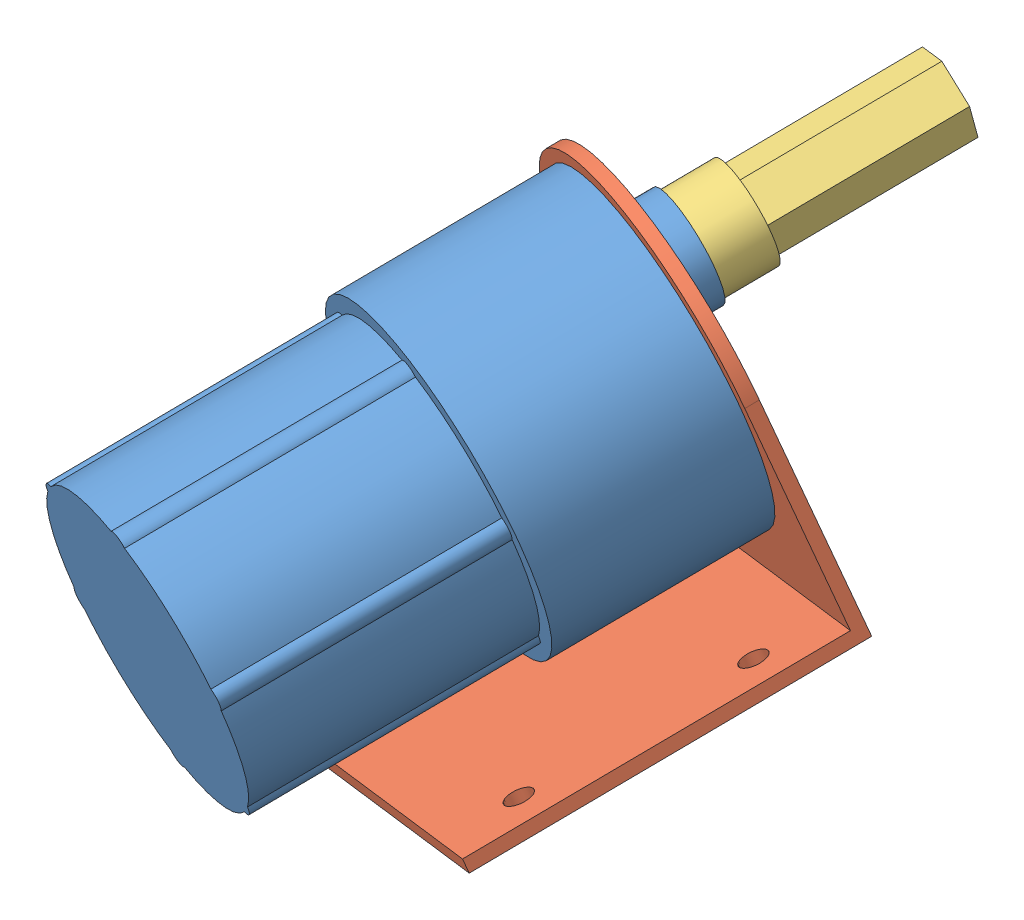
SolidWorks assembly 装配-37电机, configuration 默认. Lengths in mm.
Overall size (66.71 67.99 90.46).
3 component instances, 3 part files, 6 mates.
Components (placement in the parent):
- 37电机-1: 37电机 [默认] at (-167.9129 37.4306 415.8289) x (0.881426 0.294846 0.368991) z (-0.28336 -0.294926 0.912538) size (37 37 71)
- 电机支架-1: 电机支架 [默认] at (-167.9129 37.4306 415.8289) x (-0.881426 -0.294846 -0.368991) z (0.28336 0.294926 -0.912538) size (40 45 41.5)
- 六角联轴器-1: 六角联轴器 [默认] at (-167.1577 47.3319 406.1133) x (0.113456 0.934547 0.337269) z (-0.28336 -0.294926 0.912538) size (11 11 27)
Mates (geometry in assembly coordinates):
- 同心1: concentric aligned: cylinder of 37电机-1 through (-168.8579 45.5624 411.5885) axis (-0.28336 -0.294926 0.912538) radius 6; cylinder of 电机支架-1 through (-170.133 44.2352 415.6949) axis (-0.28336 -0.294926 0.912538) radius 6
- 重合3: coincident anti-aligned: plane of 37电机-1 through (-167.9129 37.4306 415.8289) normal (0.28336 0.294926 -0.912538); plane of 电机支架-1 through (-167.9129 37.4306 415.8289) normal (-0.28336 -0.294926 0.912538)
- 同心2: concentric anti-aligned: cylinder of 37电机-1 through (-168.9879 48.9668 430.1819) axis (0.28336 0.294926 -0.912538) radius 1.5; cylinder of 电机支架-1 through (-165.7293 52.3584 419.6877) axis (-0.28336 -0.294926 0.912538) radius 1.5
- 同心3: concentric aligned: circle of 37电机-1; circle of 六角联轴器-1
- 重合4: coincident anti-aligned: plane of 37电机-1 through (-166.2127 39.2001 410.3537) normal (0.28336 0.294926 -0.912538); plane of 六角联轴器-1 through (-168.8579 45.5624 411.5885) normal (-0.28336 -0.294926 0.912538)
- 平行1: parallel aligned: line of 电机支架-1 through (-175.6693 9.2537 402.6701) axis (0.881426 0.294846 0.368991); line of 六角联轴器-1 through (-161.7345 49.1819 385.3825) axis (0.881426 0.294846 0.368991)
